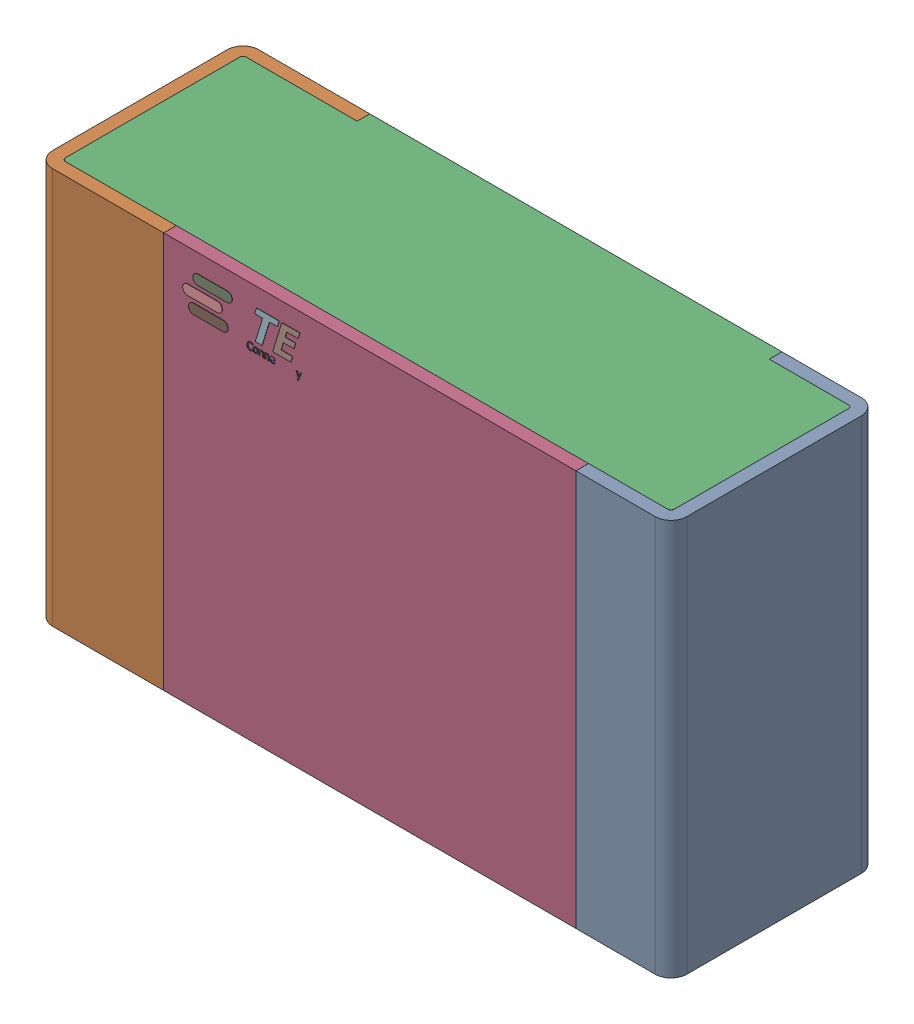
SolidWorks assembly R12.step, configuration Default. Lengths in mm.
Overall size (2 1.25 0.65).
5 component instances, 4 part files, 0 mates.
Components (placement in the parent):
- Res_TE_Connectivity_CPF0805B66R5E1_eec.step-1: Res_TE_Connectivity_CPF0805B66R5E1_eec.step [Default] at (57.277 19.431 0) size (2 1.25 0.65)
  - 1.step-1: 1.step [Default] at origin size (2 1.25 0.65)
  - 2.step-1: 2.step [Default] at origin size (1.92 1.25 0.61)
  - 3.step-1: 3.step [Default] at origin size (1.3 1.25 0.04)
  - TE connectivity Logo 1 (2).step-1: TE connectivity Logo 1 (2).step [Default] at (5.4285 0.313 0.551) x (-1 0 0) z (0 0 1) size (0.37 0.13 0.11)
